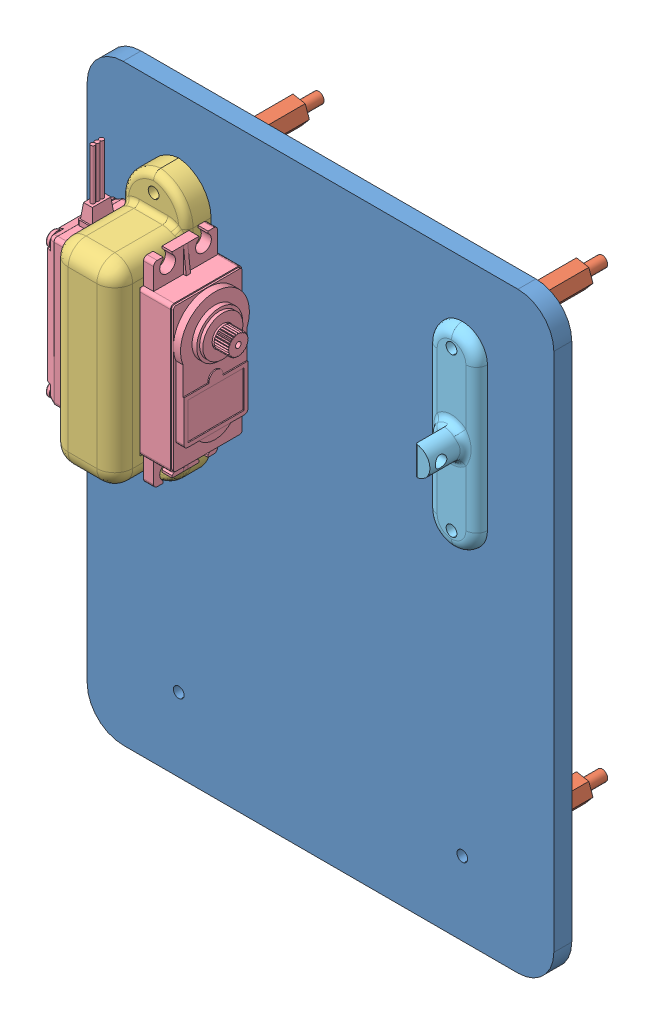
SolidWorks assembly Garra, configuration Valor predeterminado. Lengths in mm.
Overall size (130 165 65.81).
8 component instances, 5 part files, 42 mates.
Components (placement in the parent):
- Chassi-Cima-1: Chassi-Cima [Valor predeterminado] at (-114.9775 87.1344 -212.0857) size (130 165 5)
- Standoff-Nylon-5: Standoff-Nylon [Valor predeterminado] at (-80.3866 202.0259 -240.0857) size (6.82 6.52 34)
- Standoff-Nylon-6: Standoff-Nylon [Valor predeterminado] at (-159.3866 202.0259 -240.0857) size (6.82 6.52 34)
- Standoff-Nylon-7: Standoff-Nylon [Valor predeterminado] at (-159.3866 78.0259 -240.0857) size (6.82 6.52 34)
- Standoff-Nylon-8: Standoff-Nylon [Valor predeterminado] at (-80.3866 78.0259 -240.0857) size (6.82 6.52 34)
- Suporte-Servo-MG-1: Suporte-Servo-MG [Valor predeterminado] at (-139.6947 166.9981 -194.7902) x (0 -1 0) z (-1 0 0) size (74.72 26.81 18)
- Servo-MG-995-2: Servo-MG-995 [Valor predeterminado] at (-160.1947 162.9406 -197.1857) x (0 0 -1) z (0 -1 0) size (19.8 44.48 67)
- Mancal-1: Mancal [Valor predeterminado] at (-65.0421 187.4248 -207.0857) x (0 -1 0) z (0 0 1) size (54 14 13)
Mates (geometry in assembly coordinates):
- Concêntrico4: concentric anti-aligned: circle of Chassi-Cima-1; circle of Standoff-Nylon-5
- Coincidente8: coincident anti-aligned: plane of Chassi-Cima-1 through (-164.1947 205.7406 -212.0857) normal (0 0 -1); plane of Standoff-Nylon-5 through (-80.3866 202.0259 -212.0857) normal (0 0 1)
- Concêntrico5: concentric anti-aligned: circle of Chassi-Cima-1; circle of Standoff-Nylon-6
- Coincidente10: coincident anti-aligned: plane of Chassi-Cima-1 through (-164.1947 205.7406 -212.0857) normal (0 0 -1); plane of Standoff-Nylon-6 through (-159.3866 202.0259 -212.0857) normal (0 0 1)
- Concêntrico6: concentric anti-aligned: circle of Chassi-Cima-1; circle of Standoff-Nylon-7
- Coincidente12: coincident anti-aligned: plane of Chassi-Cima-1 through (-164.1947 205.7406 -212.0857) normal (0 0 -1); plane of Standoff-Nylon-7 through (-159.3866 78.0259 -212.0857) normal (0 0 1)
- Concêntrico7: concentric anti-aligned: circle of Chassi-Cima-1; circle of Standoff-Nylon-8
- Coincidente14: coincident anti-aligned: plane of Chassi-Cima-1 through (-164.1947 205.7406 -212.0857) normal (0 0 -1); plane of Standoff-Nylon-8 through (-80.3866 78.0259 -212.0857) normal (0 0 1)
- Coincidente20: coincident anti-aligned: plane of Chassi-Cima-1 through (-156.9803 36.4113 -18.6694) normal (0 1 0); plane of ? through (-155.9895 36.4113 4.227) normal (0 -1 0)
- Coincidente21: coincident anti-aligned: plane of Chassi-Cima-1 through (-139.4803 36.4113 -18.6694) normal (1 0 0); plane of ? through (-139.4803 36.4113 -18.6694) normal (-1 0 0)
- Coincidente22: coincident aligned: plane of Chassi-Cima-1 through (-224.4803 91.4113 -23.6694) normal (0 0 -1); plane of ? through (-139.4803 36.4113 -23.6694) normal (0 0 -1)
- Coincidente26: coincident anti-aligned: plane of Chassi-Cima-1 through (-106.4803 26.4113 -18.6694) normal (0 -1 0); plane of ? through (-106.4803 26.4113 -18.6694) normal (0 1 0)
- Coincidente27: coincident anti-aligned: plane of Chassi-Cima-1 through (-106.4803 1.4113 -18.6694) normal (-1 0 0); plane of ? through (-106.4803 -33.5887 21.3306) normal (1 0 0)
- Coincidente28: coincident aligned: plane of Chassi-Cima-1 through (-224.4803 91.4113 -23.6694) normal (0 0 -1); plane of ? through (-106.4803 -53.5887 -23.6694) normal (0 0 -1)
- Coincidente32: coincident anti-aligned: plane of Chassi-Cima-1 through (-232.4803 26.4113 -18.6694) normal (0 -1 0); plane of ? through (-229.4803 26.4113 -18.6694) normal (0 1 0)
- Coincidente33: coincident anti-aligned: plane of Chassi-Cima-1 through (-229.4803 26.4113 -18.6694) normal (-1 0 0); plane of ? through (-229.4803 -33.5887 11.3306) normal (1 0 0)
- Coincidente34: coincident aligned: plane of Chassi-Cima-1 through (-224.4803 91.4113 -23.6694) normal (0 0 -1); plane of ? through (-229.4803 1.4113 -23.6694) normal (0 0 -1)
- Concêntrico8: concentric anti-aligned: circle of ?; circle of ?
- Concêntrico9: concentric anti-aligned: circle of ?; circle of ?
- Coincidente40: coincident anti-aligned: plane of ? through (-109.4803 -33.5887 21.3306) normal (-1 0 0); plane of ? through (-109.4803 -45.2137 18.7306) normal (1 0 0)
- Coincidente44: coincident anti-aligned: plane of ? through (-109.4803 -31.9637 -4.0194) normal (0 0 1); plane of ? through (-121.9803 -52.0137 -4.0194) normal (0 0 -1)
- Coincidente45: coincident anti-aligned: plane of ? through (-121.9803 -23.4758 23.3806) normal (1 0 0); plane of ? through (-121.9803 -52.0137 -4.0194) normal (-1 0 0)
- Coincidente46: coincident anti-aligned: plane of ? through (-121.9803 -45.2137 18.7306) normal (0 -1 0); plane of ? through (-109.4803 -45.2137 18.6806) normal (0 1 0)
- Coincidente47: coincident aligned: plane of Chassi-Cima-1 through (-234.4803 -53.5887 -18.6694) normal (-1 0 0); plane of ? through (-234.4803 71.2813 -8.6694) normal (-1 0 0)
- Coincidente48: coincident anti-aligned: plane of Chassi-Cima-1 through (-224.4803 91.4113 -18.6694) normal (0 0 1); plane of ? through (-197.6203 91.4113 -18.6694) normal (0 0 -1)
- Distância1: distance = 10 mm aligned: plane of ? through (-197.6203 91.4113 1.3306) normal (0 1 0); plane of Chassi-Cima-1 through (-224.4803 101.4113 -18.6694) normal (0 1 0)
- Coincidente56: coincident anti-aligned: plane of Chassi-Cima-1 through (-164.1947 205.7406 -207.0857) normal (0 0 1); plane of Suporte-Servo-MG-1 through (-157.6947 142.6406 -207.0857) normal (0 0 -1)
- Coincidente58: coincident anti-aligned: plane of Chassi-Cima-1 through (-200.5747 91.4113 -60.0337) normal (0 0 1); plane of ? through (-184.5747 -35.7473 -60.0337) normal (0 0 -1)
- Tangente1: tangent anti-aligned: cylinder of Suporte-Servo-MG-1 through (-189.5747 83.9113 -33.2237) axis (0 0 -1) radius 5; plane of ? through (-184.5747 -15.4473 -50.1337) normal (-1 0 0)
- Coincidente60: coincident aligned: plane of Suporte-Servo-MG-1 through (-202.5747 81.9113 -40.2237) normal (0 -1 0); plane of ? through (-184.5747 81.9113 -60.0337) normal (0 -1 0)
- Coincidente61: coincident anti-aligned: plane of Chassi-Cima-1 through (-164.1947 205.7406 -207.0857) normal (0 0 1); plane of Servo-MG-995-2 through (-139.6947 183.2406 -207.0857) normal (0 0 -1)
- Coincidente62: coincident anti-aligned: plane of Suporte-Servo-MG-1 through (-157.6947 142.6406 -187.2757) normal (0 1 0); plane of Servo-MG-995-2 through (-139.6947 142.6406 -187.2857) normal (0 -1 0)
- Tangente2: tangent anti-aligned: cylinder of Suporte-Servo-MG-1 through (-144.6947 140.6406 -180.2757) axis (0 0 1) radius 5; plane of Servo-MG-995-2 through (-139.6947 162.9406 -197.1857) normal (-1 0 0)
- Concêntrico12: concentric aligned: circle of Standoff-Nylon-5; circle of ?
- Concêntrico13: concentric anti-aligned: circle of Chassi-Cima-1; circle of ?
- Coincidente63: coincident anti-aligned: plane of Chassi-Cima-1 through (-204.5527 141.3435 -74.9786) normal (0 0 1); plane of ? through (-123.0583 138.1831 -74.9786) normal (0 0 -1)
- Concêntrico14: concentric anti-aligned: circle of Chassi-Cima-1; circle of Mancal-1
- Coincidente67: coincident anti-aligned: plane of Chassi-Cima-1 through (-164.1947 205.7406 -207.0857) normal (0 0 1); plane of Mancal-1 through (-65.0421 187.4248 -207.0857) normal (0 0 -1)
- Concêntrico18: concentric anti-aligned: circle of Chassi-Cima-1; circle of Mancal-1
- Concêntrico19: concentric anti-aligned: circle of Standoff-Nylon-6; circle of Suporte-Servo-MG-1
- Concêntrico20: concentric aligned: circle of Servo-MG-995-2; circle of ?
- Coincidente71: coincident anti-aligned: plane of Servo-MG-995-2 through (-139.7499 161.7657 -160.8111) normal (1 0 0); plane of ? through (-139.7499 168.4357 -156.8111) normal (-1 0 0)
